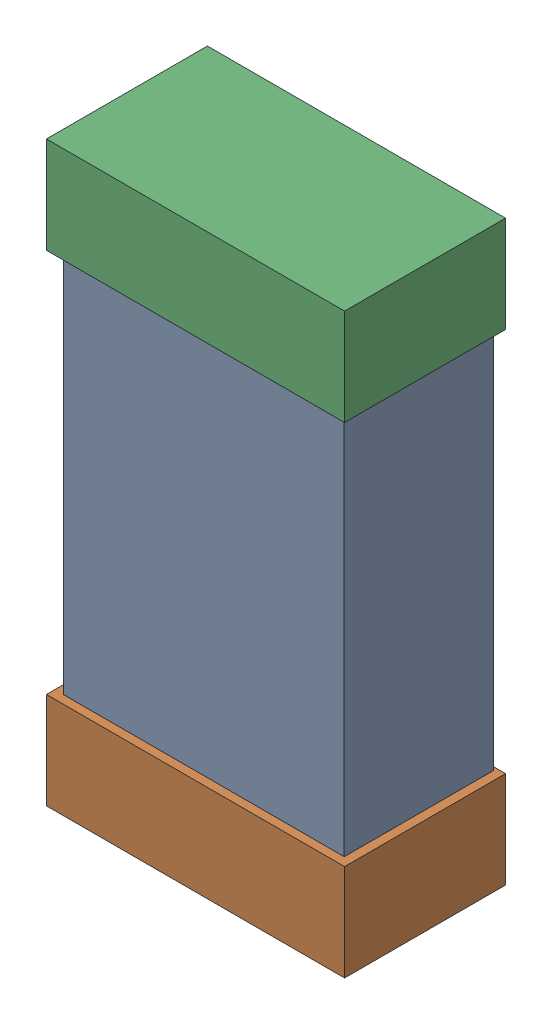
SolidWorks assembly R9, configuration Default. Lengths in mm.
Overall size (0.85 1.65 0.46).
6 component instances, 2 part files, 0 mates.
Components (placement in the parent):
- 432124816_48-1: 432124816_48 [Default] at (34.9751 24.9001 -0.8615) size (0.8 1.5 0.42)
  - Extruded (1)-1: Extruded (1) [Default] at origin size (0.8 1.5 0.42)
- 432138512_96-1: 432138512_96 [Default] at (34.9751 24.2143 -0.8715) size (0.85 0.28 0.46)
  - Extruded-1: Extruded [Default] at origin size (0.85 0.28 0.46)
- 432138512_97-1: 432138512_97 [Default] at (34.9751 25.5859 -0.8715) size (0.85 0.28 0.46)
  - Extruded-1: Extruded [Default] at origin size (0.85 0.28 0.46)
